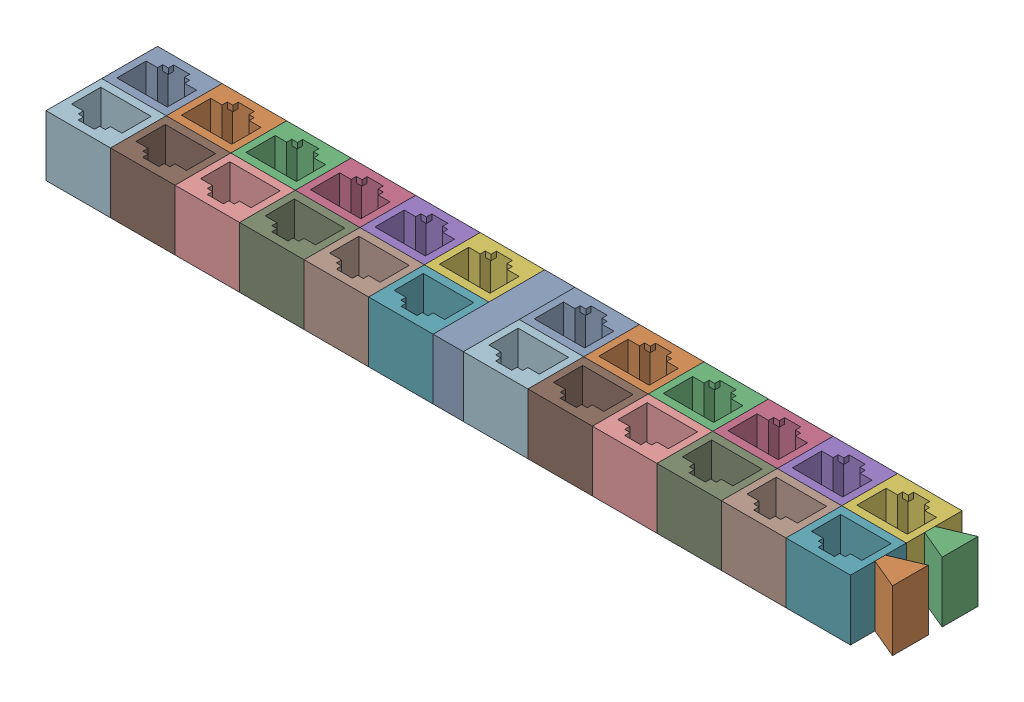
SolidWorks assembly 24-port 12-group block - half 1, configuration Default. Lengths in mm.
Overall size (207 15 27.66).
32 component instances, 3 part files, 10 mates.
Components (placement in the parent):
- 12-port block-1: 12-port block [Default] at (-94.0967 0.4985 1.7032) size (96 15 27.66)
  - 6-port block-1: 6-port block [Default] at (18.7671 16.9181 15.9423) size (96 15 13.83)
    - RJ45 dummy jack trimmed-1: RJ45 dummy jack trimmed [Default] at (-42.6786 6.807 34.1283) size (16 15 13.83)
    - RJ45 dummy jack trimmed-2: RJ45 dummy jack trimmed [Default] at (-26.6786 6.807 34.1283) size (16 15 13.83)
    - RJ45 dummy jack trimmed-3: RJ45 dummy jack trimmed [Default] at (-10.6786 6.807 34.1283) size (16 15 13.83)
    - RJ45 dummy jack trimmed-4: RJ45 dummy jack trimmed [Default] at (5.3214 6.807 34.1283) size (16 15 13.83)
    - RJ45 dummy jack trimmed-5: RJ45 dummy jack trimmed [Default] at (21.3214 6.807 34.1283) size (16 15 13.83)
    - RJ45 dummy jack trimmed-6: RJ45 dummy jack trimmed [Default] at (37.3214 6.807 34.1283) size (16 15 13.83)
  - 6-port block-2: 6-port block [Default] at (25.9098 16.9181 88.1988) x (-1 0 0) z (0 0 -1) size (96 15 13.83)
    - RJ45 dummy jack trimmed-1: RJ45 dummy jack trimmed [Default] at (-42.6786 6.807 34.1283) size (16 15 13.83)
    - RJ45 dummy jack trimmed-2: RJ45 dummy jack trimmed [Default] at (-26.6786 6.807 34.1283) size (16 15 13.83)
    - RJ45 dummy jack trimmed-3: RJ45 dummy jack trimmed [Default] at (-10.6786 6.807 34.1283) size (16 15 13.83)
    - RJ45 dummy jack trimmed-4: RJ45 dummy jack trimmed [Default] at (5.3214 6.807 34.1283) size (16 15 13.83)
    - RJ45 dummy jack trimmed-5: RJ45 dummy jack trimmed [Default] at (21.3214 6.807 34.1283) size (16 15 13.83)
    - RJ45 dummy jack trimmed-6: RJ45 dummy jack trimmed [Default] at (37.3214 6.807 34.1283) size (16 15 13.83)
- 12-port block-2: 12-port block [Default] at (9.4033 0.4985 1.7032) size (96 15 27.66)
  - 6-port block-1: 6-port block [Default] at (18.7671 16.9181 15.9423) size (96 15 13.83)
    - RJ45 dummy jack trimmed-1: RJ45 dummy jack trimmed [Default] at (-42.6786 6.807 34.1283) size (16 15 13.83)
    - RJ45 dummy jack trimmed-2: RJ45 dummy jack trimmed [Default] at (-26.6786 6.807 34.1283) size (16 15 13.83)
    - RJ45 dummy jack trimmed-3: RJ45 dummy jack trimmed [Default] at (-10.6786 6.807 34.1283) size (16 15 13.83)
    - RJ45 dummy jack trimmed-4: RJ45 dummy jack trimmed [Default] at (5.3214 6.807 34.1283) size (16 15 13.83)
    - RJ45 dummy jack trimmed-5: RJ45 dummy jack trimmed [Default] at (21.3214 6.807 34.1283) size (16 15 13.83)
    - RJ45 dummy jack trimmed-6: RJ45 dummy jack trimmed [Default] at (37.3214 6.807 34.1283) size (16 15 13.83)
  - 6-port block-2: 6-port block [Default] at (25.9098 16.9181 88.1988) x (-1 0 0) z (0 0 -1) size (96 15 13.83)
    - RJ45 dummy jack trimmed-1: RJ45 dummy jack trimmed [Default] at (-42.6786 6.807 34.1283) size (16 15 13.83)
    - RJ45 dummy jack trimmed-2: RJ45 dummy jack trimmed [Default] at (-26.6786 6.807 34.1283) size (16 15 13.83)
    - RJ45 dummy jack trimmed-3: RJ45 dummy jack trimmed [Default] at (-10.6786 6.807 34.1283) size (16 15 13.83)
    - RJ45 dummy jack trimmed-4: RJ45 dummy jack trimmed [Default] at (5.3214 6.807 34.1283) size (16 15 13.83)
    - RJ45 dummy jack trimmed-5: RJ45 dummy jack trimmed [Default] at (21.3214 6.807 34.1283) size (16 15 13.83)
    - RJ45 dummy jack trimmed-6: RJ45 dummy jack trimmed [Default] at (37.3214 6.807 34.1283) size (16 15 13.83)
- RJ45 spacer block-1: RJ45 spacer block [Default] at (-23.7582 24.2236 67.6037) size (7.5 15 27.66)
- RJ45 spacer block negative-1: RJ45 spacer block negative [Default] at (79.7418 24.2236 67.9292) size (7.5 15 21.2)
Mates (geometry in assembly coordinates):
- Coincident2: coincident anti-aligned: plane of 12-port block-1/6-port block-1/RJ45 dummy jack trimmed-6 through (-23.7582 49.2236 39.9437) normal (1 0 0); plane of RJ45 spacer block-1 through (-23.7582 49.2236 67.6037) normal (-1 0 0)
- Coincident3: coincident: point of 12-port block-1/6-port block-1/RJ45 dummy jack trimmed-6; moEndPointRef_w of RJ45 spacer block-1
- Coincident4: coincident: unknown of 12-port block-1/6-port block-1/RJ45 dummy jack trimmed-6; unknown of RJ45 spacer block-1
- Coincident5: coincident anti-aligned: plane of 12-port block-2/6-port block-1/RJ45 dummy jack trimmed-1 through (-16.2582 49.2236 39.9437) normal (-1 0 0); plane of RJ45 spacer block-1 through (-16.2582 49.2236 67.6037) normal (1 0 0)
- Coincident6: coincident: unknown of 12-port block-2/6-port block-1/RJ45 dummy jack trimmed-1; unknown of RJ45 spacer block-1
- Coincident7: coincident: unknown of 12-port block-2/6-port block-1/RJ45 dummy jack trimmed-1; unknown of RJ45 spacer block-1
- Coincident17: coincident anti-aligned: plane of 12-port block-2/6-port block-1/RJ45 dummy jack trimmed-6 through (79.7418 49.2236 39.9437) normal (1 0 0); plane of RJ45 spacer block negative-1 through (79.7418 49.2236 67.9292) normal (-1 0 0)
- Coincident22: coincident anti-aligned: plane of 12-port block-2/6-port block-1/RJ45 dummy jack trimmed-6 through (79.7418 49.2236 39.9437) normal (1 0 0); plane of RJ45 spacer block negative-1 through (79.7418 49.2236 67.9292) normal (-1 0 0)
- Coincident23: coincident anti-aligned: line of 12-port block-2/6-port block-1/RJ45 dummy jack trimmed-6 through (79.7418 49.2236 53.7737) axis (0 0 -1); line of RJ45 spacer block negative-1 through (79.7418 49.2236 46.6512) axis (0 0 1)
- Coincident24: coincident: unknown of RJ45 spacer block negative-1
